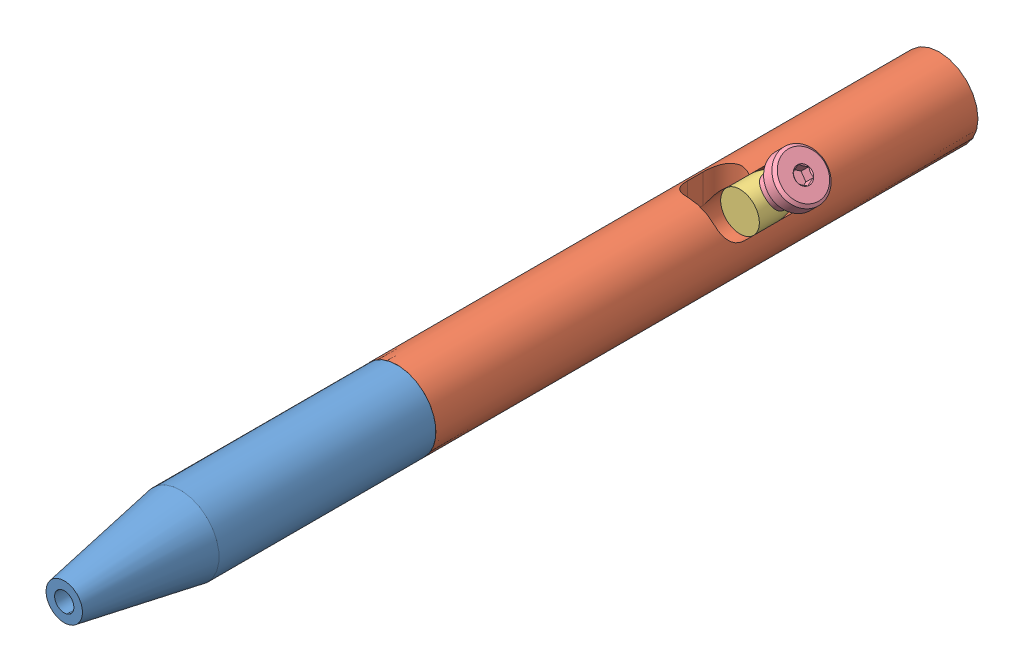
SolidWorks assembly Pen Assembly, configuration Default. Lengths in mm.
Overall size (16.18 16.18 143.51).
4 component instances, 4 part files, 8 mates.
Components (placement in the parent):
- Pen Top-1: Pen Top [Default] at (26.4077 58.252 47.0047) size (12.7 12.7 67.31)
- Pen Shaft-1: Pen Shaft [Default] at (26.4077 58.252 59.7047) x (0 1 0) z (0 0 -1) size (12.7 12.7 88.9)
- Slider Cylinder-1: Slider Cylinder [Default] at (26.4077 58.252 -9.214) x (-0.707107 0.707107 0) z (0 0 1) size (6.35 6.35 12.7)
- 90665A125_LOW-PROFILE ALLOY STEEL SOCKET HEAD CAP SCREW-1: 90665A125_LOW-PROFILE ALLOY STEEL SOCKET HEAD CAP SCREW [90665A125] at (27.5303 59.3745 -0.7473) x (-0.707107 -0.707107 0) z (-0.653619 0.653619 0.381528) size (11.91 7.92 7.92)
Mates (geometry in assembly coordinates):
- Coincident1: coincident: plane of Pen Top-1 through (26.4077 58.252 59.7047) normal (0 0 -1); plane of Pen Shaft-1 through (26.4077 58.252 59.7047) normal (0 0 1)
- Concentric1: concentric: cylinder of Pen Top-1 through (26.4077 58.252 59.7047) axis (0 0 -1) radius 4.7625; cylinder of Pen Shaft-1 through (26.4077 58.252 -29.1953) axis (0 0 1) radius 6.35
- Parallel3: parallel: plane of Pen Shaft-1 through (26.4077 58.252 59.7047) normal (0 1 0); plane of assembly through (0 0 0) normal (0 1 0)
- Concentric2: concentric: cylinder of Pen Shaft-1 through (26.4077 58.252 -29.1953) axis (0 0 1) radius 6.35; cylinder of Slider Cylinder-1 through (26.4077 58.252 5.0354) axis (0 0 -1) radius 3.175
- Parallel4: parallel: cylinder of 90665A125_LOW-PROFILE ALLOY STEEL SOCKET HEAD CAP SCREW-1 through (30.8979 62.7421 0.8021) axis (-0.707107 -0.707107 0) radius 2.413; line of Pen Shaft-1 through (26.4077 58.252 8.9047) axis (0.707107 0.707107 0)
- Concentric5: concentric: cylinder of Slider Cylinder-1 through (24.1627 56.0069 0.8021) axis (-0.707107 -0.707107 0) radius 1.8986; cylinder of 90665A125_LOW-PROFILE ALLOY STEEL SOCKET HEAD CAP SCREW-1 through (30.8979 62.7421 0.8021) axis (-0.707107 -0.707107 0) radius 2.413
- Tangent3: tangent: cylinder of Pen Shaft-1 through (26.4077 58.252 -29.1953) axis (0 0 1) radius 6.35; plane of 90665A125_LOW-PROFILE ALLOY STEEL SOCKET HEAD CAP SCREW-1 through (31.9669 61.6731 4.4648) normal (-0.707107 -0.707107 0)
- Tangent5: tangent: curve of Pen Shaft-1; circle of 90665A125_LOW-PROFILE ALLOY STEEL SOCKET HEAD CAP SCREW-1
